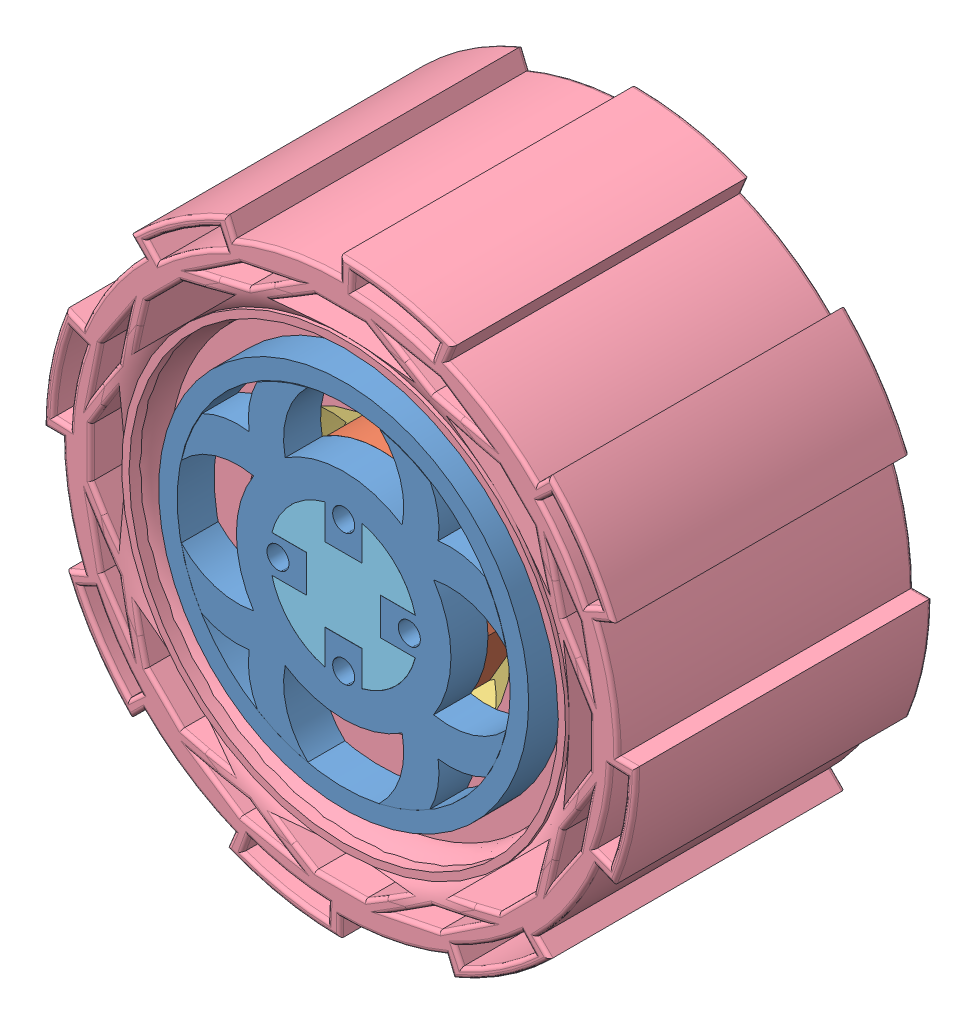
SolidWorks assembly Full_Wheel_Assembly+Brushing_Connector, configuration Default. Lengths in mm.
Overall size (160.18 160.18 92.39).
8 component instances, 5 part files, 5 mates.
Components (placement in the parent):
- Inner_Wheel_Assembly-1: Inner_Wheel_Assembly [Default] at origin size (100 100 80)
  - Outside Ring_V2-1: Outside Ring_V2 [Default] at (52.237 61.0198 67.889) size (100 100 10)
  - Outside Ring_V2-2: Outside Ring_V2 [Default] at (52.237 61.0198 -2.111) size (100 100 10)
  - Motor_Connector_Ring_V2-1: Motor_Connector_Ring_V2 [Default] at (52.237 61.0198 57.889) size (58 58 15)
  - Motor_Connector_Ring_V2-2: Motor_Connector_Ring_V2 [Default] at (52.237 61.0198 12.889) size (58 58 15)
  - Inner Ring_V2-1: Inner Ring_V2 [Default] at (52.237 61.0198 42.889) size (100 100 30)
- Tire_V2-1: Tire_V2 [Default] at (52.237 61.0198 -11.111) x (1 0 0) z (0 -1 0) size (160.18 82.78 160.18)
- Wheel_Brushing_Connector_V2-1: Wheel_Brushing_Connector_V2 [Default] at (52.2019 61.0548 67.889) x (0 0 -1) z (1 0 0) size (90 38.73 38.73)
Mates (geometry in assembly coordinates):
- Coincident2: coincident anti-aligned: plane of Inner_Wheel_Assembly-1/Inner Ring_V2-1 through (52.237 61.0198 42.889) normal (0 0 1); plane of Tire_V2-1 through (52.237 61.0198 42.889) normal (0 0 -1)
- Coincident7: coincident aligned: plane of Inner_Wheel_Assembly-1/Outside Ring_V2-1 through (52.237 61.0198 67.889) normal (0 0 1); plane of Wheel_Brushing_Connector_V2-1 through (52.2019 61.0548 67.889) normal (0 0 1)
- Coincident8: coincident anti-aligned: plane of Inner_Wheel_Assembly-1/Motor_Connector_Ring_V2-1 through (52.237 71.0198 42.889) normal (0 -1 0); plane of Wheel_Brushing_Connector_V2-1 through (52.2019 71.0198 -22.111) normal (0 1 0)
- Coincident9: coincident anti-aligned: plane of Inner_Wheel_Assembly-1/Motor_Connector_Ring_V2-1 through (42.237 61.0198 42.889) normal (1 0 0); plane of Wheel_Brushing_Connector_V2-1 through (42.237 61.0548 -22.111) normal (-1 0 0)
- Parallel1: parallel anti-aligned: plane of Inner_Wheel_Assembly-1/Outside Ring_V2-2 through (52.237 61.0198 -2.111) normal (0 0 1); plane of Tire_V2-1 through (52.237 61.0198 -1.111) normal (0 0 -1)
